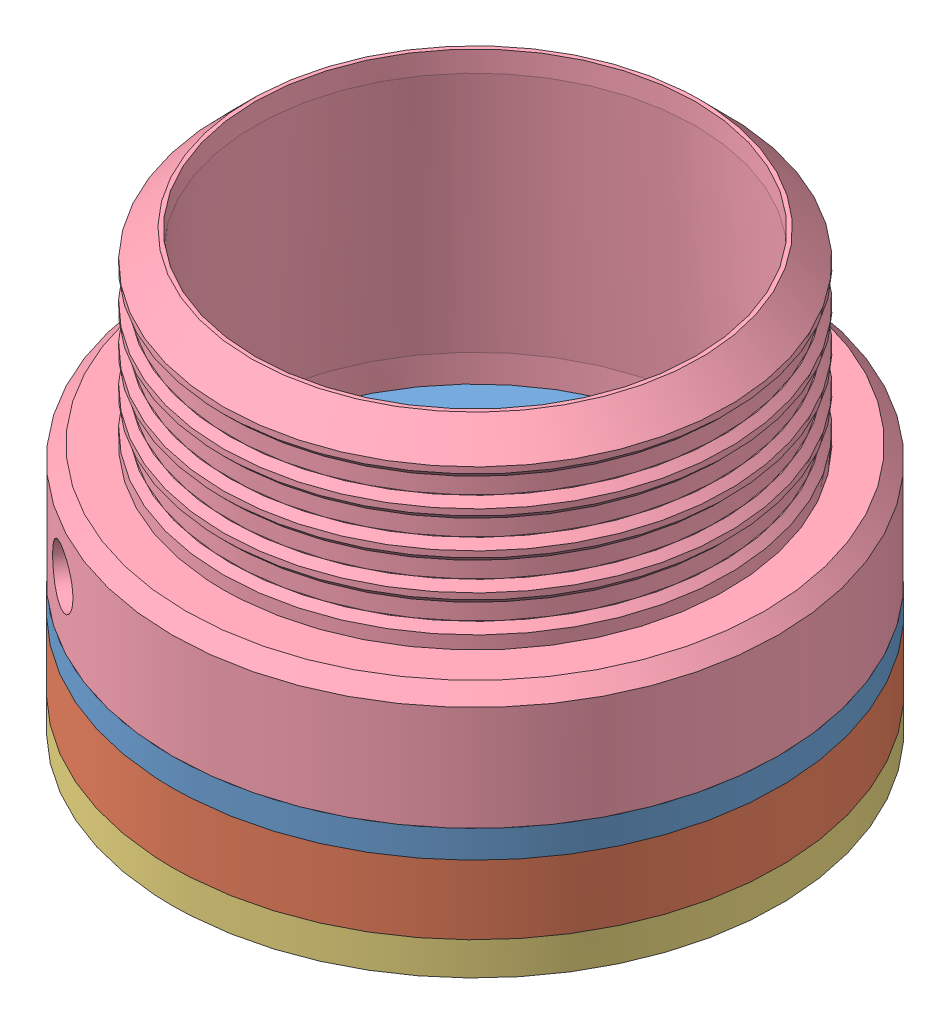
SolidWorks assembly Assem1, configuration Default. Lengths in mm.
Overall size (139.7 119.29 139.7).
5 component instances, 4 part files, 0 mates.
Components (placement in the parent):
- Injector Assembly V4-1: Injector Assembly V4 [Default] at origin size (139.7 119.29 139.7)
  - Injector V4-1: Injector V4 [Default] at origin size (139.7 6.35 139.7)
  - Distribution Plate V4-1: Distribution Plate V4 [Default] x (-1 0 0) z (0 0 1) size (139.7 25.4 139.7)
  - Top Plate V4-1: Top Plate V4 [Default] at (0 -15.875 0) x (-1 0 0) z (0 0 1) size (139.7 26.85 139.7)
  - Flange V4-1: Flange V4 [Default] at (0 71.755 0) x (-1 0 0) z (0 0 1) size (139.7 70.22 139.7)
